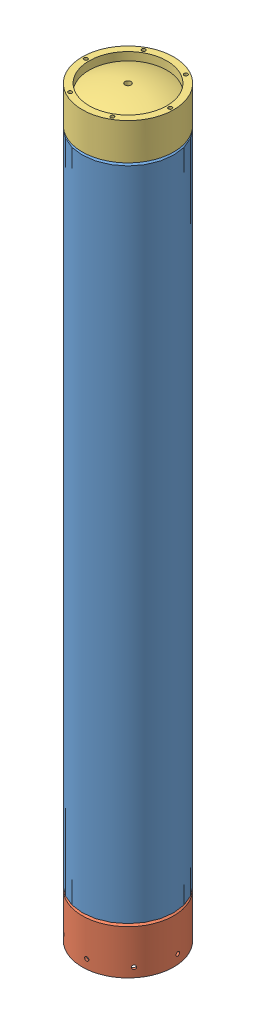
SolidWorks assembly TankAssembly, configuration Default. Lengths in mm.
Overall size (158.86 1030.53 158.86).
3 component instances, 3 part files, 4 mates.
Components (placement in the parent):
- Cylindrical Part-2: Cylindrical Part [Default] at origin size (127 914.4 127)
- End Cap-2: End Cap [Default] at (0 6.35 0) x (-0.955332 0 -0.295534) z (-0.295534 0 0.955332) size (127 69.85 127)
- Top Cap-1: Top Cap [Default] at (0 908.05 0) x (0.999996 0 0.002976) z (-0.002976 0 0.999996) size (127 58.98 127)
Mates (geometry in assembly coordinates):
- Concentric4: concentric aligned: cylinder of Cylindrical Part-2 through (0 819.187 0) axis (0 1 0) radius 63.5; cylinder of Top Cap-1 through (0 1035.111 0) axis (0 1 0) radius 63.5
- Concentric5: concentric anti-aligned: cylinder of Cylindrical Part-2 through (0 819.187 0) axis (0 1 0) radius 60.325; cylinder of End Cap-2 through (0 -120.711 0) axis (0 -1 0) radius 60.198
- Coincident1: coincident aligned: circle of Cylindrical Part-2; circle of Top Cap-1
- Coincident2: coincident anti-aligned: circle of Cylindrical Part-2; circle of End Cap-2
